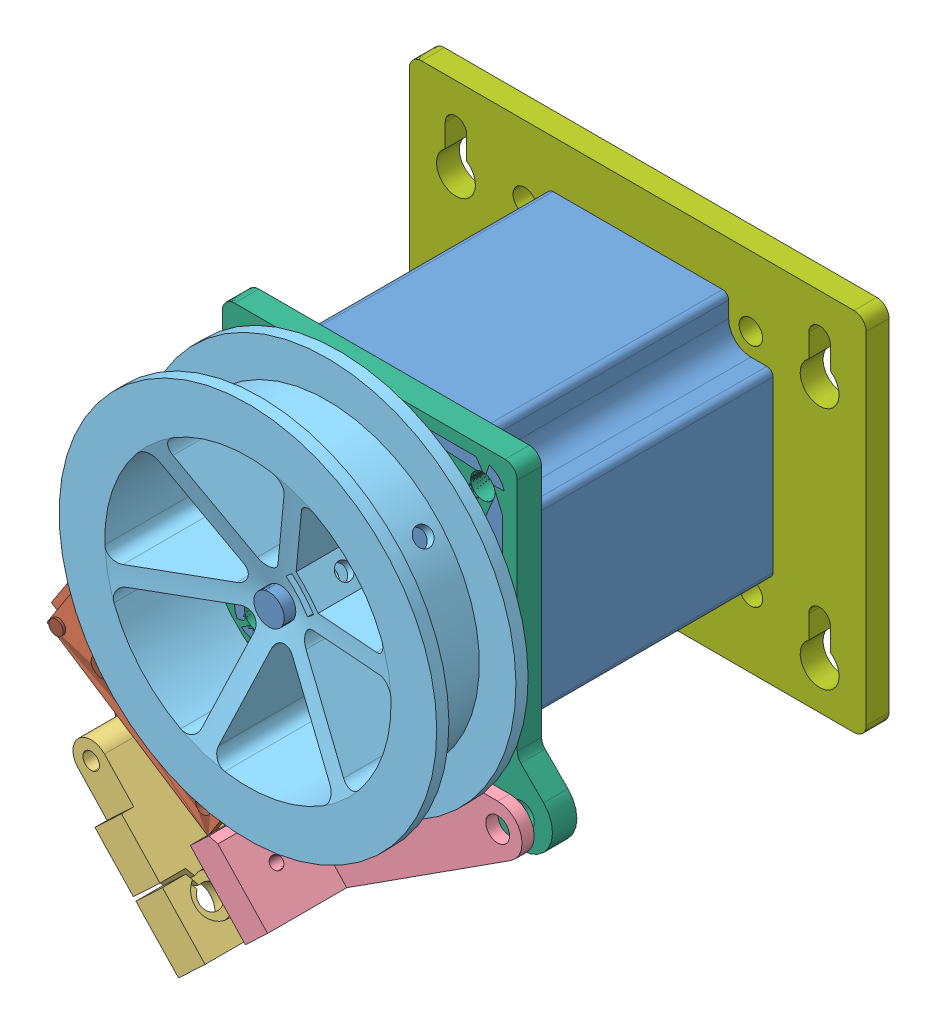
SolidWorks assembly rover_assembly3, configuration Default. Lengths in mm.
Overall size (138.25 139.12 86.04).
9 component instances, 8 part files, 20 mates.
Components (placement in the parent):
- anaheim_stepper_nema23-1: anaheim_stepper_nema23 [Default] at (3.6025 9.7468 4.1172) size (56.4 56.4 76.88)
- motor_plate-1: motor_plate [Default] at (3.6025 9.7468 11.4572) x (0 -1 0) z (0 0 -1) size (76.36 73.49 25.4) (hidden)
- limit_assembly-1: limit_assembly [Default] at (39.2666 -73.0971 45.228) x (-0.685916 0.727681 0) z (0 0 1) size (87.03 107.95 19.05)
  - mechanical_endstop-1: mechanical_endstop [Default] at (58.8161 21.2263 -22.6708) x (0.971653 0.236413 0) z (0 0 -1) size (41.88 19.5 9.76)
  - lever_bar-1: lever_bar [Default] at (59.5905 30.3176 -27.4208) size (38.1 7.62 15.24)
  - limit_plate4-1: limit_plate4 [Default] at (83.7195 -31.9124 -33.7708) size (87.03 107.95 19.05)
- string_pulley-1: string_pulley [Default] at (3.6025 9.7468 24.7922) x (-0.751113 -0.660173 0) z (0 0 -1) size (78.74 78.74 19.05)
- motor_mount-1: motor_mount [Default] at (3.6025 9.7468 8.9172) size (76.2 68.84 5.08)
- wall_plate-1: wall_plate [Default] at (3.6025 9.7468 -46.9628) x (-1 0 0) z (0 0 -1) size (95.25 76.2 4.76)
Mates (geometry in assembly coordinates):
- Concentric1: concentric anti-aligned: cylinder of anaheim_stepper_nema23-1 through (3.6025 9.7468 10.5172) axis (0 0 -1) radius 19.05; cylinder of ? through (3.6025 9.7468 11.4572) axis (0 0 1) radius 25.4
- Concentric2: concentric aligned: cylinder of anaheim_stepper_nema23-1 through (3.6025 9.7468 29.9172) axis (0 0 -1) radius 3.175; cylinder of string_pulley-1 through (3.6025 9.7468 34.3172) axis (0 0 -1) radius 3.1115
- Distance1: distance = 1.27 mm anti-aligned: plane of ? through (3.5556 9.8648 13.9972) normal (0 0 1); plane of string_pulley-1 through (-25.7742 -16.464 15.2672) normal (0 0 -1)
- Concentric4: concentric aligned: circle of anaheim_stepper_nema23-1; cylinder of motor_plate-1 through (3.6025 9.7468 8.9172) axis (0 0 1) radius 19.812
- Parallel5: parallel anti-aligned: plane of anaheim_stepper_nema23-1 through (31.8025 -14.0082 8.9172) normal (1 0 0); plane of motor_plate-1 through (32.5645 33.5018 5.1072) normal (-1 0 0)
- Coincident11: coincident anti-aligned: plane of anaheim_stepper_nema23-1 through (-20.1525 33.5018 8.9172) normal (0 0 1); plane of motor_plate-1 through (-20.1525 -14.0082 8.9172) normal (0 0 -1)
- Coincident13: coincident anti-aligned: plane of motor_plate-1 through (-20.1525 -14.0082 11.4572) normal (0 0 1); plane of ? through (3.6025 9.7468 11.4572) normal (0 0 -1)
- Concentric5: concentric aligned: cylinder of anaheim_stepper_nema23-1 through (3.6025 9.7468 29.9172) axis (0 0 -1) radius 3.175; cylinder of limit_assembly-1/limit_plate4-1 through (3.6025 9.7468 13.9972) axis (0 0 -1) radius 3.81
- Coincident15: coincident anti-aligned: plane of motor_plate-1 through (-20.1525 -14.0082 11.4572) normal (0 0 1); plane of limit_assembly-1/limit_plate4-1 through (5.0642 9.7131 11.4572) normal (0 0 -1)
- Distance2: distance = 1.27 mm anti-aligned: plane of string_pulley-1 through (-25.9688 -16.2442 15.2672) normal (0 0 -1); plane of limit_assembly-1/limit_plate4-1 through (5.0642 9.7131 13.9972) normal (0 0 1)
- InPlace1: in place: plane of anaheim_stepper_nema23-1 through (-20.1525 33.5018 8.9172) normal (0 0 1); plane of ? through (0 0 8.9172) normal (0 0 1); moOrthogonalPlaneRef_w of anaheim_stepper_nema23-1 through (-20.1525 33.5018 8.9172) normal (0 0 1); plane of ? through (0 0 8.9172) normal (0 1 0); plane of anaheim_stepper_nema23-1 through (-20.1525 33.5018 8.9172) normal (0 0 1); plane of ? through (0 0 8.9172) normal (1 0 0); plane of anaheim_stepper_nema23-1 through (-20.1525 33.5018 8.9172) normal (0 0 1); unknown of motor_mount-1
- Coincident16: coincident aligned: plane of anaheim_stepper_nema23-1; plane of motor_mount-1
- Coincident17: coincident aligned: moOrthogonalPlaneRef_w of anaheim_stepper_nema23-1 through (3.6025 9.7468 8.9172) normal (0 1 0); plane of motor_mount-1 through (3.6025 9.7468 8.9172) normal (0 1 0)
- Coincident18: coincident anti-aligned: moOrthogonalPlaneRef_w of anaheim_stepper_nema23-1 through (3.6025 9.7468 8.9172) normal (-1 0 0); plane of motor_mount-1 through (3.6025 9.7468 8.9172) normal (1 0 0)
- InPlace2: in place: plane of anaheim_stepper_nema23-1 through (-20.1525 33.5018 -46.9628) normal (0 0 -1); plane of ? through (0 0 -46.9628) normal (0 0 -1); plane of anaheim_stepper_nema23-1 through (-20.1525 33.5018 -46.9628) normal (0 0 -1); unknown of ?; plane of anaheim_stepper_nema23-1 through (-20.1525 33.5018 -46.9628) normal (0 0 -1); plane of ? through (0 0 -46.9628) normal (-1 0 0); plane of anaheim_stepper_nema23-1 through (-20.1525 33.5018 -46.9628) normal (0 0 -1); unknown of wall_plate-1
- Coincident19: coincident aligned: plane of anaheim_stepper_nema23-1; plane of wall_plate-1
- Coincident20: coincident aligned: moOrthogonalPlaneRef_w of anaheim_stepper_nema23-1 through (3.6025 9.7468 -46.9628) normal (0 1 0); plane of wall_plate-1
- Coincident21: coincident anti-aligned: moOrthogonalPlaneRef_w of anaheim_stepper_nema23-1 through (3.6025 9.7468 -46.9628) normal (1 0 0); plane of wall_plate-1 through (3.6025 9.7468 -46.9628) normal (-1 0 0)
- Concentric11: concentric aligned: cylinder of limit_assembly-1/limit_plate4-1 through (35.3525 -22.0032 11.4571) axis (0 0 1) radius 2.4892; cylinder of motor_mount-1 through (35.3525 -22.0032 8.9172) axis (0 0 1) radius 2.5527
- Concentric12: concentric aligned: cylinder of limit_assembly-1/limit_plate4-1 through (-28.1475 -22.0032 11.4571) axis (0 0 1) radius 2.4892; cylinder of motor_mount-1 through (-28.1475 -22.0032 8.9172) axis (0 0 1) radius 2.5527
